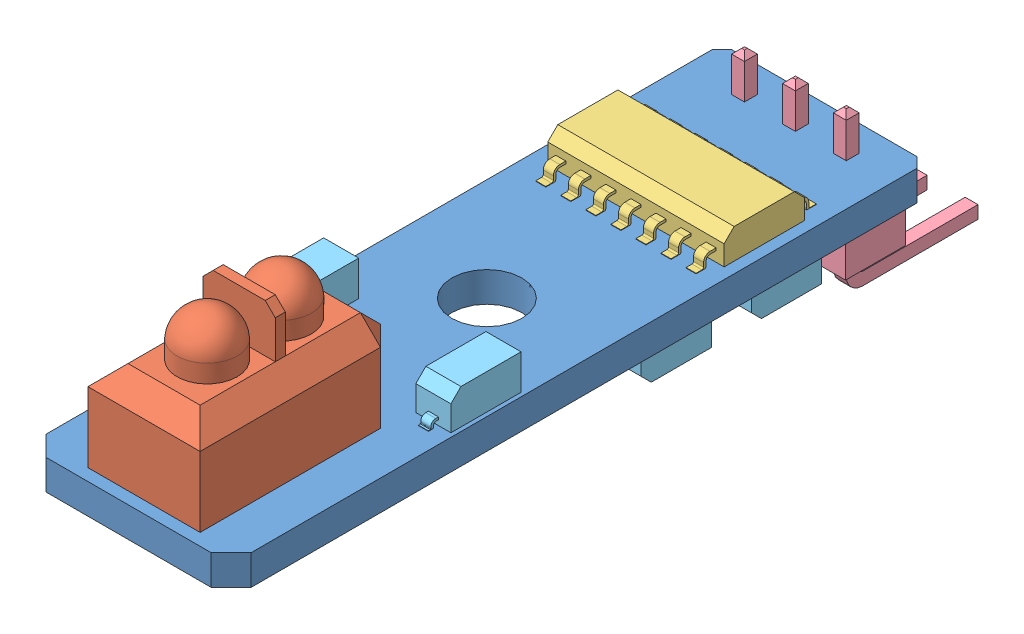
SolidWorks assembly Line Sensor, configuration Default. Lengths in mm.
Overall size (10.24 12.72 39.61).
11 component instances, 5 part files, 20 mates.
Components (placement in the parent):
- Line Sensor-1: Line Sensor [Default] at (-0.1712 -0.8535 0.6702) size (10.24 1.5 34.73)
- TCR5000-1: TCR5000 [Default] at (0 0.6465 12.4352) x (-1 0 0) z (0 1 0) size (5.6 10 6.9)
- 14 Pin SMT-1: 14 Pin SMT [Default] at (0 1.3965 -9.1146) x (0 0 1) z (-1 0 0) size (6 1.6 8.8)
- 3 Pin Header 90 Degree line-1: 3 Pin Header 90 Degree line [Default] at (0 -2.1035 -15.0723) x (0 0 1) z (1 0 0) size (8 7.82 8)
- Cap1 SMT-1: Cap1 SMT [Default] at (-4.2233 1.5215 5.121) x (0 0 1) z (-1 0 0) size (4.5 1.84 1.75)
- Cap1 SMT-4: Cap1 SMT [Default] at (3.8767 1.5215 5.121) x (0 0 1) z (-1 0 0) size (4.5 1.84 1.75)
- Cap1 SMT-6: Cap1 SMT [Default] at (-3.859 -1.7285 -4.8119) x (0 0 1) z (1 0 0) size (4.5 1.84 1.75)
- Cap1 SMT-7: Cap1 SMT [Default] at (3.441 -1.7285 -4.8119) x (0 0 1) z (1 0 0) size (4.5 1.84 1.75)
- Cap1 SMT-8: Cap1 SMT [Default] at (-3.859 -1.7285 -10.3119) x (0 0 1) z (1 0 0) size (4.5 1.84 1.75)
- Cap1 SMT-9: Cap1 SMT [Default] at (3.441 -1.7285 -10.3119) x (0 0 1) z (1 0 0) size (4.5 1.84 1.75)
- Cap1 SMT-10: Cap1 SMT [Default] at (-0.1549 -1.7285 -11.3346) x (1 0 0) z (0 0 -1) size (4.5 1.84 1.75)
Mates (geometry in assembly coordinates):
- Coincident1: coincident anti-aligned: plane of Line Sensor-1 through (4.9488 0.6465 18.0352) normal (0 1 0); plane of TCR5000-1 through (-2.8 0.6465 7.4352) normal (0 -1 0)
- Parallel1: parallel aligned: plane of Line Sensor-1 through (-5.2912 0.6465 18.0352) normal (0 0 1); plane of TCR5000-1 through (2.8 5.1465 17.4352) normal (0 0 1)
- Distance2: distance = 0.6 mm aligned: plane of TCR5000-1 through (2.8 5.1465 17.4352) normal (0 0 1); plane of Line Sensor-1 through (-5.2912 0.6465 18.0352) normal (0 0 1)
- Coincident5: coincident anti-aligned: plane of TCR5000-1; plane of assembly through (0 0 0) normal (1 0 0)
- Coincident6: coincident anti-aligned: plane of Line Sensor-1 through (4.9488 0.6465 18.0352) normal (0 1 0); plane of 14 Pin SMT-1 through (-4.4 0.6465 -11.1146) normal (0 -1 0)
- Parallel2: parallel anti-aligned: plane of Line Sensor-1 through (-5.2912 0.6465 -16.6948) normal (-1 0 0); plane of 14 Pin SMT-1 through (4.4 2.1465 -11.1146) normal (1 0 0)
- Coincident8: coincident aligned: plane of TCR5000-1; plane of 14 Pin SMT-1 through (0 1.3965 -9.1146) normal (-1 0 0)
- Coincident9: coincident anti-aligned: plane of Line Sensor-1 through (4.9488 -0.8535 18.0352) normal (0 -1 0); plane of 3 Pin Header 90 Degree line-1 through (4 -0.8535 -16.5723) normal (0 1 0)
- Parallel3: parallel aligned: plane of Line Sensor-1 through (-5.2912 0.6465 -16.6948) normal (0 0 -1); plane of 3 Pin Header 90 Degree line-1 through (4 -3.3535 -16.5723) normal (0 0 -1)
- Distance3: distance = 1.3 mm aligned: plane of 3 Pin Header 90 Degree line-1 through (-2.86 -0.8535 -15.3948) normal (0 0 -1); plane of Line Sensor-1 through (-5.2912 0.6465 -16.6948) normal (0 0 -1)
- Coincident12: coincident aligned: plane of 3 Pin Header 90 Degree line-1 through (0 -2.1035 -15.0723) normal (1 0 0); plane of assembly through (0 0 0) normal (1 0 0)
- Coincident13: coincident anti-aligned: plane of Line Sensor-1 through (4.9488 0.6465 18.0352) normal (0 1 0); plane of Cap1 SMT-1 through (-5.0983 0.6465 3.371) normal (0 -1 0)
- Parallel4: parallel anti-aligned: plane of Line Sensor-1 through (-5.2912 0.6465 -16.6948) normal (-1 0 0); plane of Cap1 SMT-1 through (-3.3483 2.3965 3.371) normal (1 0 0)
- Lock1: lock: unknown of Line Sensor-1; unknown of Cap1 SMT-1
- Coincident17: coincident anti-aligned: plane of Line Sensor-1 through (4.9488 -0.8535 18.0352) normal (0 -1 0); plane of Cap1 SMT-6 through (-2.984 -0.8535 -6.5619) normal (0 1 0)
- Lock2: lock: unknown of Line Sensor-1; unknown of Cap1 SMT-6
- Coincident19: coincident anti-aligned: plane of Line Sensor-1 through (4.9488 -0.8535 18.0352) normal (0 -1 0); plane of Cap1 SMT-10 through (-1.9049 -0.8535 -12.2096) normal (0 1 0)
- Parallel5: parallel anti-aligned: plane of 3 Pin Header 90 Degree line-1 through (4 -3.3535 -13.5723) normal (0 0 1); plane of Cap1 SMT-10 through (-1.9049 -2.6035 -12.2096) normal (0 0 -1)
- Lock3: lock: unknown of Line Sensor-1; unknown of Cap1 SMT-10
- LocalLPattern2: unknown: line of Cap1 SMT-6 through (-2.984 -2.6035 -3.5619) axis (0 0 -1); line of Cap1 SMT-6 through (-2.984 -2.6035 -6.5619) axis (-1 0 0)
